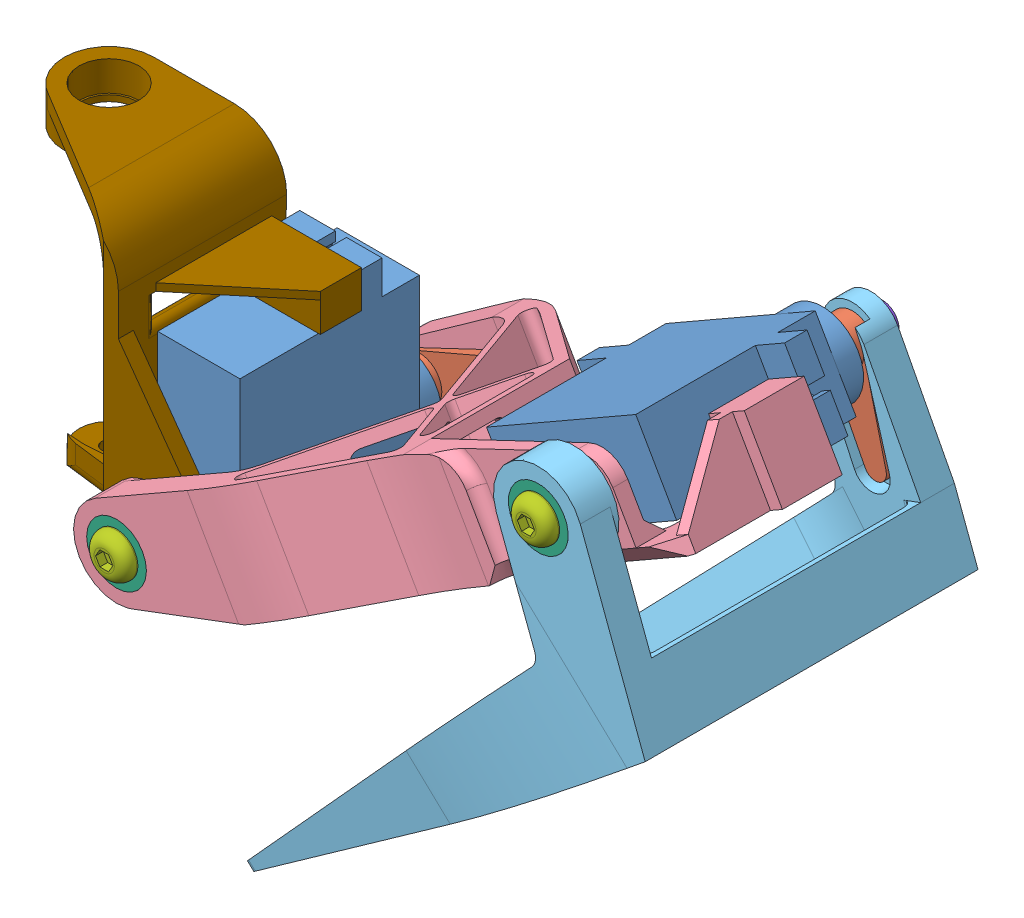
SolidWorks assembly leg, configuration Default. Lengths in mm.
Overall size (111.28 91.62 49.06).
15 component instances, 9 part files, 31 mates.
Components (placement in the parent):
- MG90S Servo-1: MG90S Servo [Default] at (8.25 19.5 18) x (0 -1 0) z (1 0 0) size (32 30 11)
- servo horn-1: servo horn [Default] at (8.25 13.5 -13) x (0.867565 0.497325 0) z (0.497325 -0.867565 0) size (17.5 3.5 6)
- threaded insert-1: threaded insert [Default] at (8.25 13.5 20.3) x (0 1 0) z (1 0 0) size (4 4.7 4)
- thight_new-1: thight_new [Default] at (48.7906 27.2302 2) x (0.867565 0.497325 0) z (0 0 1) size (81.75 14.22 44.5)
- MG90S Servo-2: MG90S Servo [Default] at (59.4363 42.8422 18) x (0.867565 0.497325 0) z (-0.497325 0.867565 0) size (32 30 11)
- threaded insert-2: threaded insert [Default] at (64.6417 45.8261 20.3) x (-0.923728 -0.383049 0) z (-0.383049 0.923728 0) size (4 4.7 4)
- servo horn-2: servo horn [Default] at (64.6417 45.8261 -13) x (0.350706 -0.936486 0) z (-0.936486 -0.350706 0) size (17.5 3.5 6)
- shin_new-1: shin_new [Default] at (99.7123 -47.8225 6.75) x (0 0 -1) z (0.936486 0.350706 0) size (49.06 60.96 90.13)
- 693zz-1: 693zz [Default] at (8.25 13.5 25) x (0.87068 -0.491851 0) z (-0.491851 -0.87068 0) size (8 4 8)
- 693zz-2: 693zz [Default] at (64.6417 45.8261 25) x (0.93765 -0.34758 0) z (-0.34758 -0.93765 0) size (8 4 8)
- m3x8 button-1: m3x8 button [Default] at (8.25 13.5 30.65) x (0 0 -1) z (1 0 0) size (9.65 5.7 5.7)
- m3x8 button-5: m3x8 button [Default] at (64.6417 45.8261 30.65) x (0 0 -1) z (1 0 0) size (9.65 5.7 5.7)
- M2.5X8 Cap Head-1: M2.5X8 Cap Head [Default] at (8.25 13.5 -17) x (0 0 1) z (-0.83083 -0.556527 0) size (8.5 4.5 4.5)
- M2.5X8 Cap Head-2: M2.5X8 Cap Head [Default] at (64.6417 45.8261 -17) x (0 0 1) z (-0.723432 0.690395 0) size (8.5 4.5 4.5)
- hip_new-1: hip_new [Default] at (84.25 22.25 6) x (0 -1 0) z (0 0 -1) size (44.79 35.75 25)
Mates (geometry in assembly coordinates):
- Concentric3: concentric aligned: cylinder of MG90S Servo-1 through (8.25 13.5 1.0711) axis (0 0 -1) radius 2.5; cylinder of servo horn-1 through (8.25 13.5 -9.5) axis (0 0 -1) radius 2.5
- Coincident3: coincident anti-aligned: plane of MG90S Servo-1 through (8.25 13.5 -12) normal (0 0 -1); plane of servo horn-1 through (8.25 13.5 -12) normal (0 0 1)
- Concentric4: concentric anti-aligned: cylinder of servo horn-1 through (8.25 13.5 -11.5) axis (0 0 -1) radius 3; cylinder of thight_new-1 through (8.25 13.5 -27) axis (0 0 1) radius 4.25
- Concentric5: concentric aligned: cylinder of servo horn-1 through (19.5283 19.9652 -11.5) axis (0 0 -1) radius 1.5; cylinder of thight_new-1 through (19.5283 19.9652 -11) axis (0 0 -1) radius 2.5
- Coincident4: coincident anti-aligned: plane of servo horn-1 through (8.25 13.5 -13) normal (0 0 -1); plane of thight_new-1 through (18.4039 25.9484 -13) normal (0 0 1)
- Concentric6: concentric anti-aligned: cylinder of thight_new-1 through (8.25 13.5 15) axis (0 0 1) radius 4; cylinder of 693zz-1 through (8.25 13.5 29) axis (0 0 -1) radius 4
- Coincident7: coincident anti-aligned: circle of 693zz-1; circle of m3x8 button-1
- Concentric8: concentric anti-aligned: cylinder of thight_new-1 through (8.25 13.5 -1.5) axis (0 0 -1) radius 1.25; cylinder of M2.5X8 Cap Head-1 through (8.25 13.5 -8.5) axis (0 0 1) radius 1.25
- Coincident8: coincident anti-aligned: plane of thight_new-1 through (8.25 13.5 -14.5) normal (0 0 -1); plane of M2.5X8 Cap Head-1 through (6.9978 15.3694 -14.5) normal (0 0 1)
- Concentric9: concentric aligned: cylinder of thight_new-1 through (71.3653 49.6804 13) axis (0 0 -1) radius 0.75; cylinder of MG90S Servo-2 through (71.3653 49.6804 3) axis (0 0 -1) radius 1.25
- Concentric10: concentric aligned: cylinder of thight_new-1 through (47.5073 36.0039 13) axis (0 0 -1) radius 0.75; cylinder of MG90S Servo-2 through (47.5073 36.0039 3) axis (0 0 -1) radius 1.25
- Coincident9: coincident anti-aligned: plane of thight_new-1 through (47.796 28.9654 2) normal (0 0 -1); plane of MG90S Servo-2 through (42.82 39.6566 2) normal (0 0 1)
- Coincident10: coincident aligned: circle of thight_new-1; circle of threaded insert-2
- Coincident11: coincident anti-aligned: circle of MG90S Servo-2; circle of servo horn-2
- Concentric11: concentric aligned: circle of servo horn-2; circle of shin_new-1
- Concentric12: concentric aligned: cylinder of servo horn-2 through (64.6417 45.8261 -11.5) axis (0 0 -1) radius 3; cylinder of shin_new-1 through (64.6417 45.8261 29.001) axis (0 0 -1) radius 4
- Coincident12: coincident anti-aligned: plane of servo horn-2 through (64.6417 45.8261 -13) normal (0 0 -1); plane of shin_new-1 through (69.2009 33.6518 -13) normal (0 0 1)
- Concentric13: concentric anti-aligned: cylinder of shin_new-1 through (64.6417 45.8261 -24.3137) axis (0 0 1) radius 4; cylinder of 693zz-2 through (64.6417 45.8261 29) axis (0 0 -1) radius 4
- Coincident13: coincident anti-aligned: plane of thight_new-1 through (64.6417 45.8261 25) normal (0 0 1); plane of 693zz-2 through (64.6417 45.8261 25) normal (0 0 -1)
- Coincident15: coincident anti-aligned: circle of 693zz-2; circle of m3x8 button-5
- Concentric14: concentric aligned: cylinder of shin_new-1 through (64.6417 45.8261 -24) axis (0 0 1) radius 1; cylinder of M2.5X8 Cap Head-2 through (64.6417 45.8261 -8.5) axis (0 0 1) radius 1.25
- Coincident16: coincident anti-aligned: plane of shin_new-1 through (64.6417 45.8261 -14.5) normal (0 0 -1); plane of M2.5X8 Cap Head-2 through (66.1951 47.4538 -14.5) normal (0 0 1)
- Concentric15: concentric anti-aligned: cylinder of threaded insert-1 through (8.25 13.5 25) axis (0 0 -1) radius 2; cylinder of hip_new-1 through (8.25 13.5 12.5) axis (0 0 1) radius 2
- Coincident17: coincident aligned: plane of threaded insert-1 through (8.25 13.5 25) normal (0 0 1); plane of hip_new-1 through (14 22.25 25) normal (0 0 1)
- Concentric16: concentric aligned: cylinder of threaded insert-1 through (8.25 13.5 25) axis (0 0 -1) radius 1.5; cylinder of m3x8 button-1 through (8.25 13.5 30.65) axis (0 0 -1) radius 1.5
- Coincident19: coincident anti-aligned: plane of MG90S Servo-1 through (13.75 35.5 2) normal (0 0 1); plane of hip_new-1 through (0 0 2) normal (0 0 -1)
- Coincident23: coincident anti-aligned: plane of thight_new-1 through (8.25 13.5 25) normal (0 0 1); plane of 693zz-1 through (8.25 13.5 25) normal (0 0 -1)
- Coincident24: coincident anti-aligned: plane of hip_new-1 through (0 22.25 6) normal (-1 0 0); plane of assembly through (0 0 0) normal (1 0 0)
- Coincident25: coincident anti-aligned: plane of hip_new-1 through (0 0 12) normal (0 -1 0); plane of assembly through (0 0 0) normal (0 1 0)
- Coincident26: coincident anti-aligned: plane of hip_new-1 through (0 44.5 0) normal (0 0 -1); plane of assembly through (0 0 0) normal (0 0 1)
- Concentric19: concentric aligned: cylinder of MG90S Servo-1 through (8.25 33.25 3) axis (0 0 -1) radius 1.25; cylinder of hip_new-1 through (8.25 33.25 25.001) axis (0 0 -1) radius 0.75
